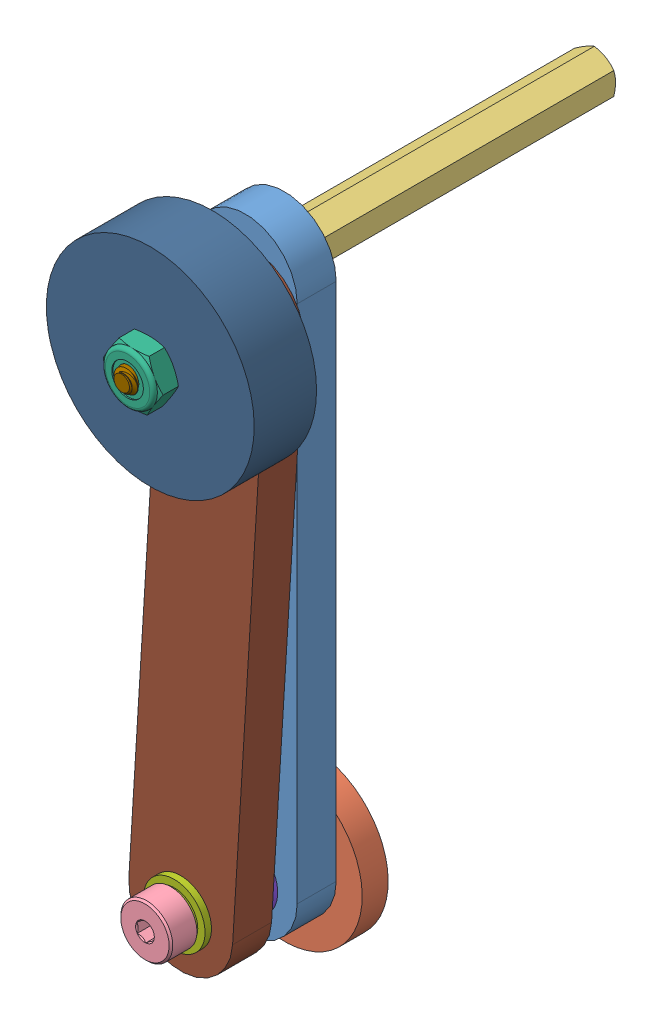
SolidWorks assembly pendulum, configuration Default. Lengths in mm.
Overall size (37.13 90.03 62.34).
18 component instances, 11 part files, 8 mates.
Components (placement in the parent):
- top_link_assy-1: top_link_assy [Default] at origin size (36.86 95.73 55.46) (flexible)
  - top_link-1: top_link [Default] at (0 0 4.7625) x (0 1 0) z (-1 0 0) size (76.2 4.76 12.7)
  - RC22-1: RC22 [Default] at (0 -63.5 -3.175) x (0.022662 -0.999743 0) z (-0.999743 -0.022662 0) size (19.05 3.17 19.05)
  - _ALUM FEM THRDED HEX STANDOFF_91780A036-1: _ALUM FEM THRDED HEX STANDOFF_91780A036 [91780A036] at (0 0 -19.05) x (0.5 0.866025 0) z (0 0 1) size (4.76 5.5 38.96)
  - 4_40-5-8_5-32-94035A136-1: 4_40-5-8_5-32-94035A136 [94035A136] at (0 -63.5 17.018) x (0.563747 -0.825948 0) z (0 0 1) size (6.35 6.35 23.39)
  - bearing_spacer_ 99040A316-1: bearing_spacer_ 99040A316 [Default] at (0 -63.5 7.0993) x (0.923728 0.383049 0) z (0 0 -1) size (4.76 4.76 0.41)
  - bearing_spacer_ 99040A316-2: bearing_spacer_ 99040A316 [Default] at (0 -63.5 13.843) x (0.923728 0.383049 0) z (0 0 -1) size (4.76 4.76 0.41)
  - 4_40_THIN_LOCKNUT_90633A005-1: 4_40_THIN_LOCKNUT_90633A005 [90633A005] at (0 -63.5 -3.175) x (0.830959 0.556334 0) z (-0.556334 0.830959 0) size (6.35 2.86 7.33)
  - FR144-ZZ-1: FR144-ZZ [Default] at (0 -63.5 10.6331) x (-0.92036 -0.391073 0) z (0 0 1) size (7.52 7.52 2.8)
  - 4_40-Washer_AL_93286A005-new-1: 4_40-Washer_AL_93286A005-new [93286A005] at (0 -63.5 5.7277) x (0 0 -1) z (1 0 0) size (0.97 7.92 7.92)
  - 4_40-Washer_AL_93286A005-new-2: 4_40-Washer_AL_93286A005-new [93286A005] at (0 -63.5 6.6929) x (0 0 -1) z (0.987351 0.158553 0) size (0.97 7.92 7.92)
  - FR144-ZZ-2: FR144-ZZ [Default] at (0 -63.5 9.9028) x (-0.83595 0.548806 0) z (0 0 -1) size (7.52 7.52 2.8)
  - 4_40-625-countersunk-91253A112-1: 4_40-625-countersunk-91253A112 [91253A112] at (0 0 4.7625) size (6.48 6.48 16.21)
- bottom_link_assy-1: bottom_link_assy [Default] at (0 -63.5 7.8867) x (-0.998113 0.061411 0) z (0 0 1) size (31.92 85.81 16.21)
  - Mass_blank-1: Mass_blank [Default] at (0 -63.5 4.7625) x (0.9527 0.303914 0) z (0 0 1) size (25.4 25.4 7.62)
  - 4_40_THIN_LOCKNUT_90633A005-1: 4_40_THIN_LOCKNUT_90633A005 [90633A005] at (0 -63.5 12.3825) x (0.853828 0.520556 0) z (0.520556 -0.853828 0) size (6.35 2.86 7.33)
  - bottom_link-1: bottom_link [Default] at (0 0 4.7625) x (0 1 0) z (-1 0 0) size (76.2 4.76 12.7)
  - 4_40-625-countersunk-91253A112-1: 4_40-625-countersunk-91253A112 [91253A112] at (0 -63.5 0) x (-0.923728 -0.383049 0) z (0 0 -1) size (6.48 6.48 16.21)
Mates (geometry in assembly coordinates):
- Coincident28: coincident anti-aligned: plane of ? through (6.35 -63.5 12.319) normal (0 0 1); plane of ? through (6.35 -63.5 12.319) normal (0 0 -1)
- Coincident33: coincident anti-aligned: plane of top_link_assy-1/top_link-1 through (0 0 0) normal (0 0 -1); plane of assembly through (0 0 0) normal (0 0 1)
- Coincident34: coincident: line of top_link_assy-1/top_link-1 through (6.35 0 0) axis (0 0 1); plane of assembly
- Symmetric2: symmetric aligned: plane of top_link_assy-1/top_link-1 through (-6.35 0 0) normal (-1 0 0); plane of top_link_assy-1/top_link-1 through (6.35 0 0) normal (1 0 0); plane of assembly through (0 0 0) normal (1 0 0)
- Concentric33: concentric aligned: cylinder of top_link_assy-1/FR144-ZZ-1 through (0 -63.5 12.6492) axis (0 0 -1) radius 1.5875; cylinder of bottom_link_assy-1/bottom_link-1 through (0 -63.5 12.6492) axis (0 0 -1) radius 3.1623
- Coincident43: coincident anti-aligned: plane of bottom_link_assy-1/bottom_link-1 through (0 -63.5 7.8867) normal (0 0 -1); plane of top_link_assy-1/FR144-ZZ-2 through (0 -63.5 7.8867) normal (0 0 1)
- Concentric34: concentric anti-aligned: cylinder of top_link_assy-1/FR144-ZZ-2 through (0 -63.5 7.8867) axis (0 0 1) radius 3.175; cylinder of bottom_link_assy-1/bottom_link-1 through (0 -63.5 12.6492) axis (0 0 -1) radius 3.1623
- Coincident44: coincident anti-aligned: plane of top_link_assy-1/FR144-ZZ-1 through (0 -63.5 12.6492) normal (0 0 -1); plane of bottom_link_assy-1/bottom_link-1 through (0 -63.5 12.6492) normal (0 0 1)
